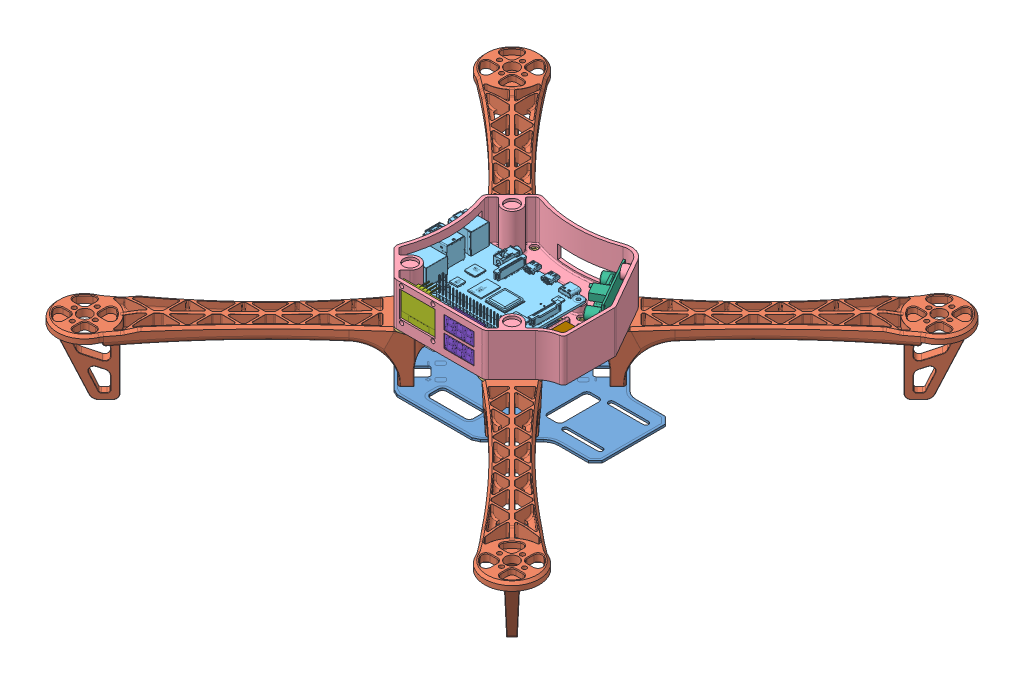
SolidWorks assembly mount_ass, configuration Default. Lengths in mm.
Overall size (375.45 86.56 375.45).
14 component instances, 9 part files, 27 mates.
Components (placement in the parent):
- Assembly-1: Assembly [Default] at (7.3032 115.5299 163.3533) size (375.45 55.34 375.45)
  - Base bottom-1: Base bottom [Default] at (67.5563 86.9564 146.6689) size (182 1.6 118)
  - arm-1: arm [Default] at (165.9237 126.3564 245.0469) x (-0.707107 0 0.707107) z (-0.707107 0 -0.707107) size (40.75 55.34 213.92)
  - arm-2: arm [Default] at (-30.8217 126.3564 245.0362) x (-0.707107 0 -0.707107) z (0.707107 0 -0.707107) size (40.75 55.34 213.92)
  - arm-3: arm [Default] at (165.9344 126.3564 48.3015) x (0.707107 0 0.707107) z (-0.707107 0 0.707107) size (40.75 55.34 213.92)
  - arm-4: arm [Default] at (-30.811 126.3564 48.2908) x (0.707107 0 -0.707107) z (0.707107 0 0.707107) size (40.75 55.34 213.92)
  - Base Top-1: Base Top [Default] at (67.5563 125.3865 146.6689) size (108.15 1.65 108.15)
- mount1-1: mount1 [Default] at (74.8595 242.5664 310.0222) size (121.3 31.65 108.65)
- Raspberry Pi 4 model B-1: Raspberry Pi 4 model B [Default] at (60.8595 249.1914 310.0222) x (-1 0 0) z (0 0 -1) size (89 19.92 58.4)
- BuckConverter-1: BuckConverter [Default] at (122.0128 259.8414 282.561) x (-0.496539 0 -0.868014) z (0 -1 0) size (43.15 12.85 21.8)
- OLED TFT 0.96 inch 64x128 monochrome-1: OLED TFT 0.96 inch 64x128 monochrome [Default] at (58.4692 273.1914 360.3972) x (1 0 0) z (0 -1 0) size (27.3 12.3 27.8)
- VoltageLCD_Assy-1: VoltageLCD_Assy [Default] at (81.661 233.2552 329.3993) size (33 11.5 8)
- VoltageLCD_Assy-2: VoltageLCD_Assy [Default] at (81.661 245.2552 329.3993) size (33 11.5 8)
- bn0880q-1: bn0880q [Default] at (109.5818 246.3914 334.6916) size (30 9.5 30)
Mates (geometry in assembly coordinates):
- Coincident1: coincident anti-aligned: plane of Assembly-1/mount1-1 through (25.46 241.7414 278.2819) normal (0 1 0); plane of mount1-1 through (106.5999 241.7414 260.6227) normal (0 -1 0)
- Concentric1: concentric aligned: circle of Assembly-1/mount1-1; circle of mount1-1
- Concentric2: concentric aligned: circle of Assembly-1/mount1-1; circle of mount1-1
- Coincident4: coincident anti-aligned: plane of mount1-1 through (106.5999 243.3914 260.6227) normal (0 1 0); plane of Rpi_4_Case_Bottom-1 through (31.2808 243.3914 387.3576) normal (0 -1 0)
- Coincident5: coincident anti-aligned: plane of Assembly-1/Base Top-1 through (106.5999 241.7414 260.6227) normal (0 1 0); plane of mount1-1 through (106.5999 241.7414 260.6227) normal (0 -1 0)
- Concentric4: concentric aligned: cylinder of Assembly-1/Base Top-1; cylinder of mount1-1 through (106.3258 233.9632 261.9389) axis (0 1 0) radius 2.75
- Parallel3: parallel anti-aligned: line of mount1-1 through (101.8595 243.3914 319.5222) axis (0 0 -1); line of Rpi_4_Case_Bottom-1 through (107.7427 267.3914 307.7656) axis (0 0 1)
- Concentric5: concentric aligned: circle of mount1-1; circle of Raspberry Pi 4 model B-1
- Concentric6: concentric aligned: circle of Assembly-1/Base Top-1; circle of mount1-1
- Concentric7: concentric aligned: circle of mount1-1; circle of Raspberry Pi 4 model B-1
- Concentric8: concentric aligned: circle of mount1-1; circle of Raspberry Pi 4 model B-1
- Coincident7: coincident anti-aligned: plane of mount1-1 through (74.8595 248.3914 310.0222) normal (0 1 0); plane of Raspberry Pi 4 model B-1 through (60.8595 248.3914 310.0222) normal (0 -1 0)
- Concentric19: concentric anti-aligned: circle of mount1-1; circle of OLED TFT 0.96 inch 64x128 monochrome-1
- Concentric20: concentric anti-aligned: circle of mount1-1; circle of OLED TFT 0.96 inch 64x128 monochrome-1
- Coincident15: coincident anti-aligned: plane of mount1-1 through (74.8595 336.9212 361.5972) normal (0 0 -1); plane of OLED TFT 0.96 inch 64x128 monochrome-1 through (58.4692 273.1914 361.5972) normal (0 0 1)
- Concentric25: concentric aligned: circle of mount1-1; circle of BuckConverter-1
- Concentric26: concentric aligned: circle of mount1-1; circle of BuckConverter-1
- Coincident26: coincident anti-aligned: plane of mount1-1 through (123.308 242.5664 282.3077) normal (-0.868014 0 0.496539); plane of BuckConverter-1 through (123.0978 259.8414 281.9403) normal (0.868014 0 -0.496539)
- Coincident28: coincident anti-aligned: plane of mount1-1 through (106.5999 243.3914 260.6227) normal (0 1 0); plane of bn0880q-1 through (109.5818 243.3914 334.6916) normal (0 -1 0)
- Coincident29: coincident anti-aligned: plane of mount1-1 through (74.8595 250.8914 334.6916) normal (0 0 -1); plane of bn0880q-1 through (109.5818 247.8914 334.6916) normal (0 0 1)
- Coincident30: coincident anti-aligned: plane of mount1-1 through (109.5818 250.8914 310.0222) normal (1 0 0); plane of bn0880q-1 through (109.5818 247.8914 334.6916) normal (-1 0 0)
- Concentric27: concentric aligned: circle of mount1-1; circle of VoltageLCD_Assy-2
- Concentric28: concentric aligned: circle of mount1-1; circle of VoltageLCD_Assy-1
- Coincident35: coincident: plane of mount1-1 through (74.8595 242.5664 356.5972) normal (0 0 -1); plane of VoltageLCD_Assy-2 through (101.0692 270.9914 356.5972) normal (0 0 1)
- Coincident36: coincident: plane of mount1-1 through (74.8595 242.5664 356.5972) normal (0 0 -1); plane of VoltageLCD_Assy-1 through (101.0692 258.9914 356.5972) normal (0 0 1)
- Concentric31: concentric: circle of mount1-1; circle of VoltageLCD_Assy-1
- Concentric32: concentric: circle of mount1-1; circle of VoltageLCD_Assy-2
